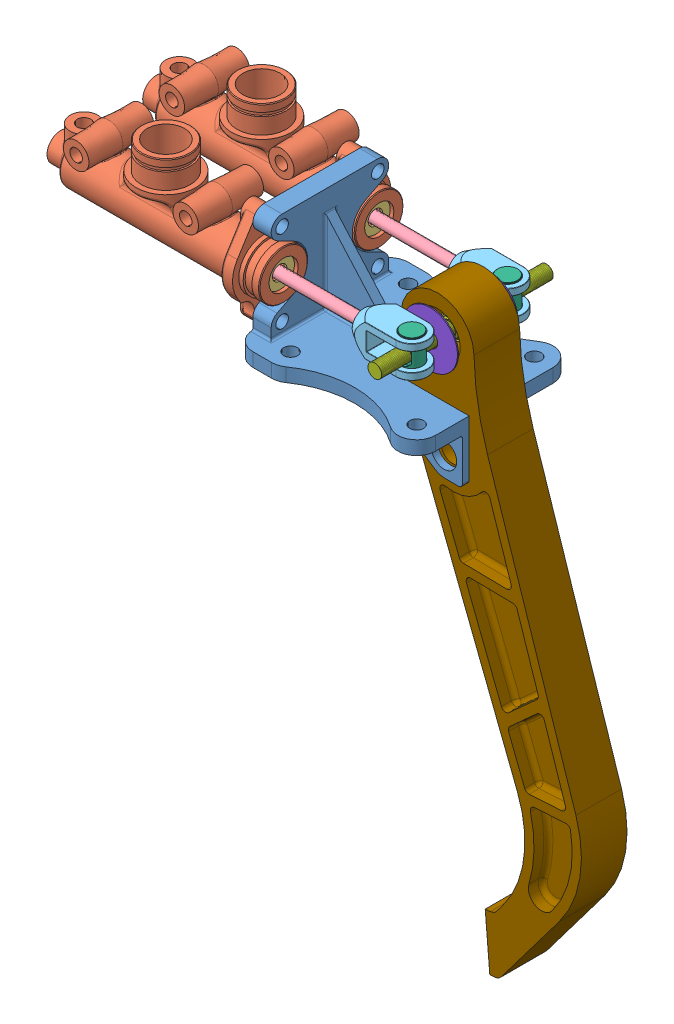
SolidWorks assembly BR22-1200-BASM, configuration Default. Lengths in mm.
Overall size (389.96 409.12 121.21).
18 component instances, 10 part files, 27 mates.
Components (placement in the parent):
- PedalMastercylMount-1: PedalMastercylMount [Default] at (-61.6568 -16.4521 -5.96) size (127.05 113.66 107.95)
- mastercylinder asm-1: mastercylinder asm [Default] at (-69.6578 12.1229 27.314) x (0 0 -1) z (1 0 0) size (45.21 75.99 223.71)
  - mastercylinder-1: mastercylinder [Default] at origin size (45.21 75.99 154.88)
  - mastercylinder retaining washer-1: mastercylinder retaining washer [Default] at (0 0 17.145) size (20.83 20.83 1.91)
  - mastercylinder pushrod-1: mastercylinder pushrod [Default] at (0 0 90.551) x (-0.12806 0.991766 0) z (0 0 1) size (10.67 10.67 107.24)
- mastercylinder asm-2: mastercylinder asm [Default] at (-69.6578 12.1229 -39.234) x (0 0 -1) z (1 0 0) size (45.21 75.99 223.71)
  - mastercylinder-1: mastercylinder [Default] at origin size (45.21 75.99 154.88)
  - mastercylinder retaining washer-1: mastercylinder retaining washer [Default] at (0 0 17.145) size (20.83 20.83 1.91)
  - mastercylinder pushrod-1: mastercylinder pushrod [Default] at (0 0 90.551) x (-0.12806 0.991766 0) z (0 0 1) size (10.67 10.67 107.24)
- clevis-1: clevis [Default] at (41.4545 0.9469 27.5045) x (0 0 -1) z (1 0 0) size (21.97 22.28 44.25)
- clevis-2: clevis [Default] at (41.4545 0.9469 -39.0435) x (0 0 -1) z (1 0 0) size (21.97 22.28 44.25)
- clevis pin-3: clevis pin [Default] at (41.4545 0.2865 -39.0435) size (14.27 23.6 14.27)
- clevis pin-4: clevis pin [Default] at (41.4545 0.2865 27.5045) size (14.27 23.6 14.27)
- Balance bar-2: Balance bar [Default] at (41.5999 12.1359 -6.2775) x (-0.943579 -0.331147 0) z (-0.331147 0.943579 0) size (20.15 121.21 20.15)
- bushing-1: bushing [Default] at (41.6783 12.1634 14.2965) x (0 0 -1) z (0.852085 -0.523404 0) size (12.65 12.65 49.7)
- Washer-1: Washer [Default] at (41.6783 12.1634 15.0585) x (0 0 -1) z (0.988589 -0.150638 0) size (0.76 38.1 38.1)
- Washer-2: Washer [Default] at (41.6783 12.1634 -26.3435) x (0 0 -1) z (0.984471 -0.175545 0) size (0.76 38.1 38.1)
- brakepedaltest1-1: brakepedaltest1 [Default] at (52.6432 -51.3771 -5.96) x (0 0 1) z (-0.940935 -0.338587 0) size (31.75 384.44 115.48)
Mates (geometry in assembly coordinates):
- Coincident1: coincident anti-aligned: plane of PedalMastercylMount-1 through (-61.6568 12.1229 27.314) normal (-1 0 0); plane of mastercylinder asm-1/mastercylinder-1 through (-61.6568 40.6979 27.314) normal (1 0 0)
- Concentric1: concentric aligned: cylinder of PedalMastercylMount-1 through (-48.9568 40.6979 27.314) axis (-1 0 0) radius 4.3656; cylinder of mastercylinder asm-1/mastercylinder-1 through (-61.6568 40.6979 27.314) axis (-1 0 0) radius 4.3656
- Concentric2: concentric aligned: cylinder of PedalMastercylMount-1 through (-48.9568 -16.4521 27.314) axis (-1 0 0) radius 4.3656; cylinder of mastercylinder asm-1/mastercylinder-1 through (-61.6568 -16.4521 27.314) axis (-1 0 0) radius 4.3656
- Coincident2: coincident anti-aligned: plane of PedalMastercylMount-1 through (-61.6568 12.1229 27.314) normal (-1 0 0); plane of mastercylinder asm-2/mastercylinder-1 through (-61.6568 40.6979 -39.234) normal (1 0 0)
- Concentric3: concentric aligned: cylinder of PedalMastercylMount-1 through (-48.9568 40.6979 -39.234) axis (-1 0 0) radius 4.3656; cylinder of mastercylinder asm-2/mastercylinder-1 through (-61.6568 40.6979 -39.234) axis (-1 0 0) radius 4.3656
- Concentric4: concentric aligned: cylinder of PedalMastercylMount-1 through (-48.9568 -16.4521 -39.234) axis (-1 0 0) radius 4.3656; cylinder of mastercylinder asm-2/mastercylinder-1 through (-61.6568 -16.4521 -39.234) axis (-1 0 0) radius 4.3656
- Concentric8: concentric anti-aligned: cylinder of mastercylinder asm-1/mastercylinder pushrod-1 through (20.8932 12.1229 27.314) axis (1 0 0) radius 3.81; circle of clevis-1
- Concentric13: concentric anti-aligned: cylinder of mastercylinder asm-2/mastercylinder pushrod-1 through (20.8932 12.1229 -39.234) axis (1 0 0) radius 3.81; circle of clevis-2
- Coincident4: coincident aligned: plane of mastercylinder asm-2/mastercylinder pushrod-1 through (20.8932 12.1229 -39.234) normal (1 0 0); plane of clevis-2 through (20.8932 18.4348 -26.3435) normal (1 0 0)
- Coincident5: coincident aligned: plane of mastercylinder asm-1/mastercylinder pushrod-1 through (20.8932 12.1229 27.314) normal (1 0 0); plane of clevis-1 through (20.8932 18.4348 40.2045) normal (1 0 0)
- Coincident6: coincident aligned: plane of clevis-1 through (41.4545 23.2227 27.5045) normal (0 1 0); plane of clevis-2 through (41.4545 23.2227 -39.0435) normal (0 1 0)
- Concentric14: concentric anti-aligned: cylinder of clevis pin-4 through (41.4545 12.0848 20.329) axis (0 0 1) radius 4.7625; circle of Balance bar-2
- Concentric15: concentric aligned: circle of clevis pin-3; circle of Balance bar-2
- Concentric16: concentric aligned: cylinder of clevis-1 through (41.4545 23.2227 27.5045) axis (0 -1 0) radius 7.239; cylinder of clevis pin-4 through (41.4545 23.8831 27.5045) axis (0 -1 0) radius 7.1374
- Tangent5: tangent anti-aligned: plane of clevis-1 through (52.44 5.7348 40.2045) normal (0 1 0); cylinder of clevis pin-4 through (41.4545 12.0848 20.3671) axis (0 0 1) radius 6.35
- Concentric17: concentric aligned: cylinder of clevis-2 through (41.4545 23.2227 -39.0435) axis (0 -1 0) radius 7.239; cylinder of clevis pin-3 through (41.4545 23.8831 -39.0435) axis (0 -1 0) radius 7.1374
- Tangent6: tangent anti-aligned: plane of clevis-2 through (52.44 5.7348 -26.3435) normal (0 1 0); cylinder of clevis pin-3 through (41.4545 12.0848 -46.1809) axis (0 0 1) radius 6.35
- Concentric18: concentric: circle of Balance bar-2; cylinder of Bushing-1 through (41.6783 12.1634 -26.3435) axis (0 0 1) radius 12.7
- Distance1: distance = 18.796 mm anti-aligned: plane of Balance bar-2 through (41.5999 12.1359 -15.1675) normal (0 0 -1); plane of clevis pin-3 through (41.4545 12.0848 -33.9635) normal (0 0 1)
- Distance2: distance = 11.176 mm: plane of Balance bar-2 through (41.5999 12.1359 -15.1675) normal (0 0 -1); plane of Bushing-1 through (41.6783 12.1634 -26.3435) normal (0 0 -1)
- Concentric19: concentric: cylinder of Bushing-1 through (41.6783 12.1634 -26.3435) axis (0 0 1) radius 15.875; circle of Washer-1
- Coincident14: coincident: plane of Bushing-1 through (41.6783 12.1634 14.2965) normal (0 0 1); plane of Washer-1 through (41.6783 12.1634 14.2965) normal (0 0 -1)
- Concentric20: concentric: cylinder of Bushing-1 through (41.6783 12.1634 -26.3435) axis (0 0 1) radius 15.875; circle of Washer-2
- Coincident15: coincident: plane of Bushing-1 through (41.6783 12.1634 -26.3435) normal (0 0 -1); plane of Washer-2 through (41.6783 12.1634 -26.3435) normal (0 0 1)
- Concentric21: concentric: cylinder of Bushing-1 through (41.6783 12.1634 -26.3435) axis (0 0 1) radius 15.875; cylinder of brakepedaltest1-1 through (41.6783 12.1634 9.915) axis (0 0 -1) radius 15.875
- Distance3: distance = 1.5875 mm anti-aligned: plane of brakepedaltest1-1 through (52.6432 -51.3771 -21.835) normal (0 0 -1); plane of PedalMastercylMount-1 through (65.3432 -33.5971 -23.4225) normal (0 0 1)
- Concentric22: concentric aligned: circle of PedalMastercylMount-1; cylinder of brakepedaltest1-1 through (52.6432 -51.3771 9.915) axis (0 0 -1) radius 8.8004
